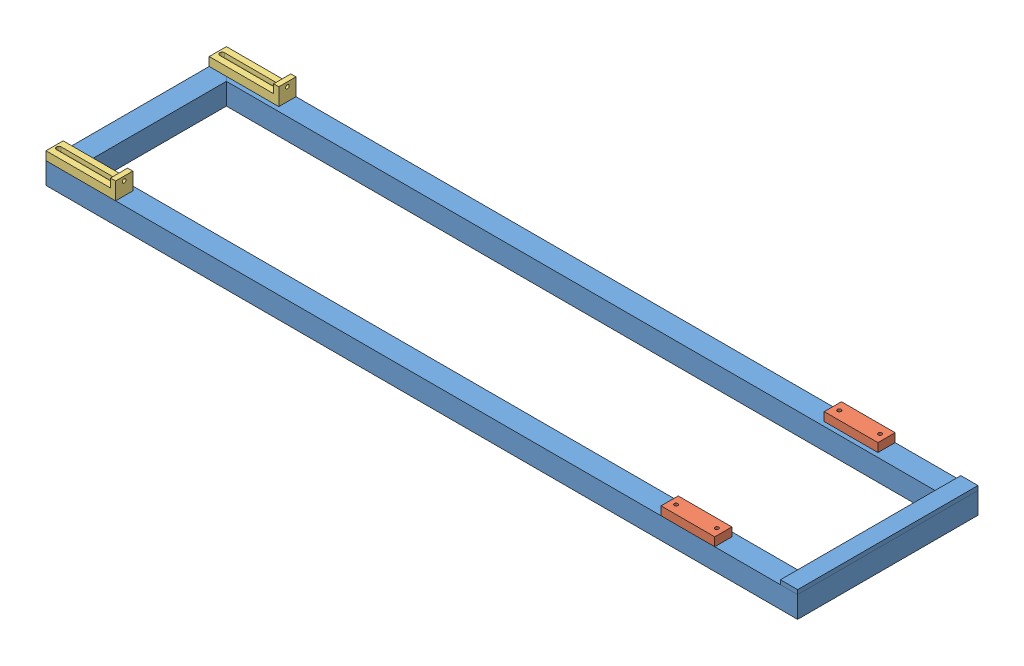
SolidWorks assembly 机架, configuration 默认. Lengths in mm.
Overall size (1750 90 445.97).
5 component instances, 3 part files, 6 mates.
Components (placement in the parent):
- 方框-1: 方框 [默认<按加工>] at origin size (1750 60 420)
- 轴承板焊接件1-1: 轴承板焊接件1 [默认<按加工>] at (619.5 25 -190) size (125 20 65.97)
- 轴承板焊接件1-3: 轴承板焊接件1 [默认<按加工>] at (619.5 25 190) size (125 20 65.97)
- 轴承板焊接件2-1: 轴承板焊接件2 [默认] at (-800 25 -190) size (162 40 65.97)
- 轴承板焊接件2-2: 轴承板焊接件2 [默认] at (-800 25 190) size (162 40 65.97)
Mates (geometry in assembly coordinates):
- 重合1: coincident anti-aligned: plane of 方框-1 through (-850 25 -160) normal (0 1 0); plane of 轴承板焊接件1-1 through (619.5 25 -190) normal (0 -1 0)
- 距离1: distance = 0 mm aligned: plane of 轴承板焊接件1-1 through (557 45 -210) normal (0 0 -1); plane of 方框-1 through (-850 25 -210) normal (0 0 -1)
- 重合5: coincident anti-aligned: plane of 方框-1 through (-850 25 -160) normal (0 1 0); plane of 轴承板焊接件2-1 through (-800 25 -190) normal (0 -1 0)
- 重合6: coincident aligned: plane of 轴承板焊接件1-1 through (557 45 -210) normal (0 0 -1); plane of 轴承板焊接件2-1 through (-875 45 -210) normal (0 0 -1)
- 距离4: distance = 1432 mm aligned: plane of 轴承板焊接件1-1 through (557 45 -210) normal (-1 0 0); plane of 轴承板焊接件2-1 through (-875 45 -210) normal (-1 0 0)
- 重合13: coincident aligned: plane of 方框-1 through (-875 25 185) normal (-1 0 0); plane of 轴承板焊接件2-1 through (-875 45 -210) normal (-1 0 0)
